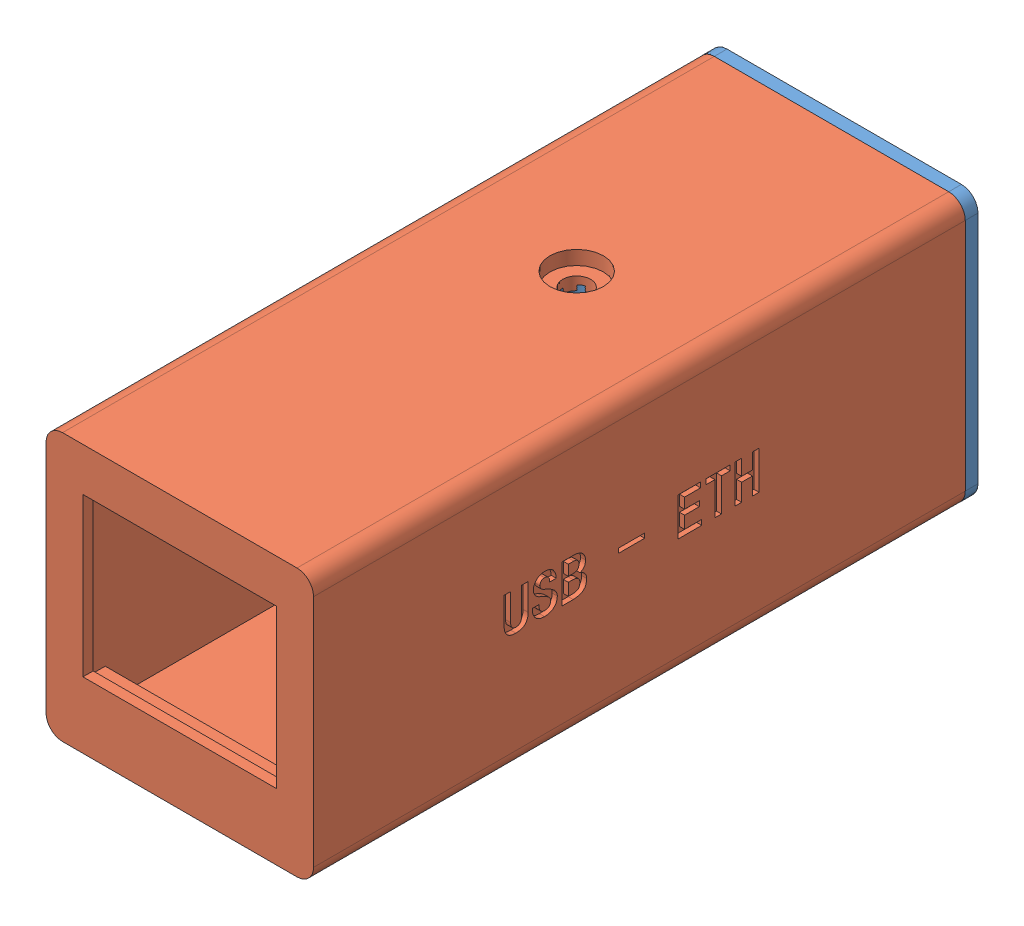
SolidWorks assembly 装配体1, configuration 默认. Lengths in mm.
Overall size (21 21 52.15).
2 component instances, 2 part files, 3 mates.
Components (placement in the parent):
- usb-eth-shell-back-1: usb-eth-shell-back [默认] at (-60.712 40.1721 10.99) size (21 21 28.8)
- usb-eth-shell-1: usb-eth-shell [默认] at (-60.712 40.1721 63.14) x (-1 0 0) z (0 0 -1) size (21 21 51.15)
Mates (geometry in assembly coordinates):
- 同心4: concentric anti-aligned: cylinder of usb-eth-shell-back-1 through (-51.512 30.9721 11.99) axis (0 0 -1) radius 1.3; cylinder of usb-eth-shell-1 through (-51.512 30.9721 11.99) axis (0 0 1) radius 1.3
- 同心5: concentric anti-aligned: cylinder of usb-eth-shell-back-1 through (-69.912 30.9721 11.99) axis (0 0 -1) radius 1.3; cylinder of usb-eth-shell-1 through (-69.912 30.9721 11.99) axis (0 0 1) radius 1.3
- 重合1: coincident anti-aligned: plane of usb-eth-shell-back-1 through (-69.912 30.9721 11.99) normal (0 0 1); plane of usb-eth-shell-1 through (-51.512 30.9721 11.99) normal (0 0 -1)
